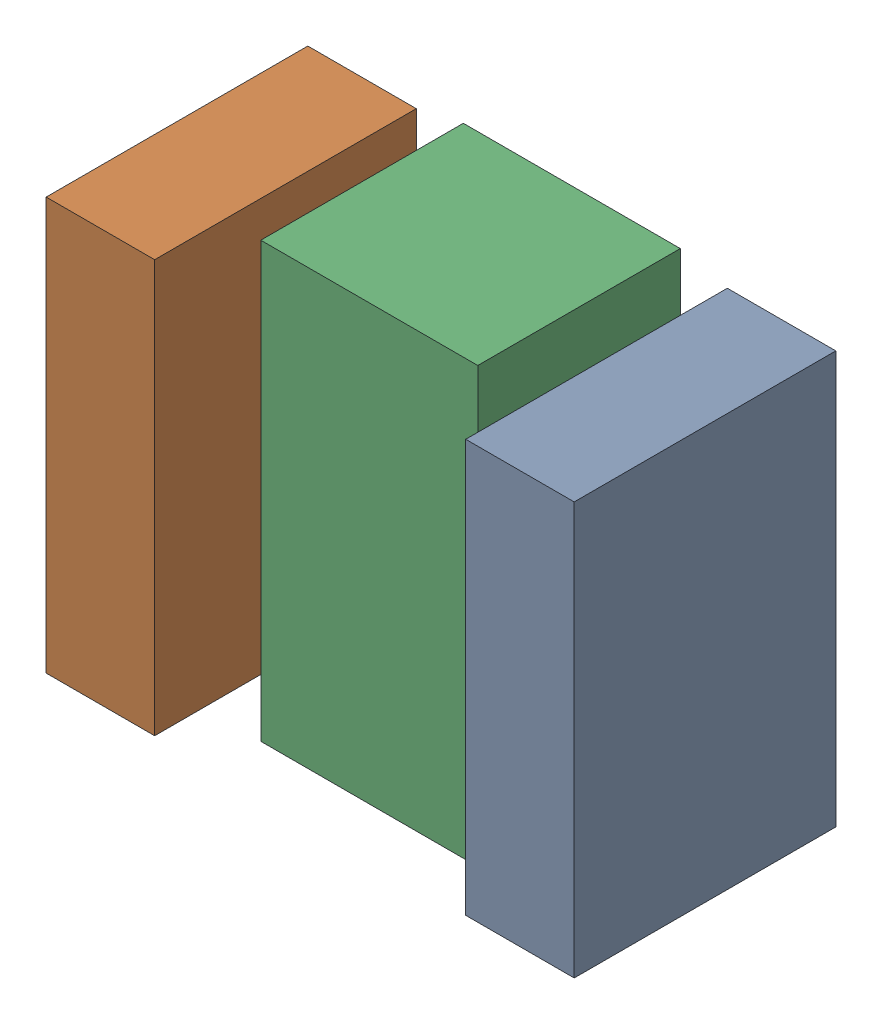
SolidWorks assembly C11_Motor_12Kanaloa_v2.0.0_Motor, configuration Default. Lengths in mm.
Overall size (3.65 3 1.81).
6 component instances, 2 part files, 0 mates.
Components (placement in the parent):
- 334788400-1: 334788400 [Default] at (64.4928 120.5484 0) size (0.75 2.85 1.81)
  - Extruded_5-1: Extruded_5 [Default] at origin size (0.75 2.85 1.81)
- 334788400-2: 334788400 [Default] at (61.5928 120.5484 0) size (0.75 2.85 1.81)
  - Extruded_5-1: Extruded_5 [Default] at origin size (0.75 2.85 1.81)
- 334788656-1: 334788656 [Default] at (63.0428 120.5484 0) size (1.5 3 1.4)
  - Extruded_1-1: Extruded_1 [Default] at origin size (1.5 3 1.4)
